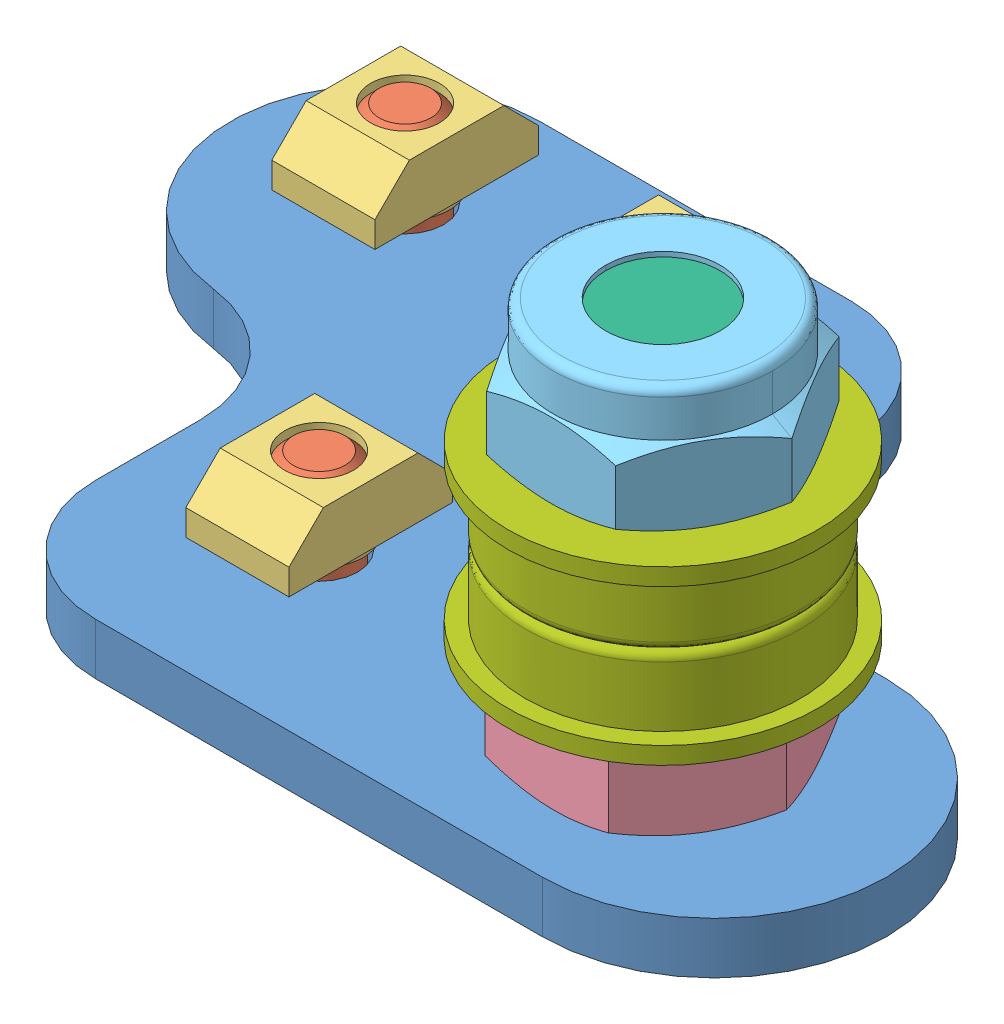
SolidWorks assembly pulley mount, configuration 默认. Lengths in mm.
Overall size (57.16 30.08 38).
12 component instances, 7 part files, 23 mates.
Components (placement in the parent):
- Y Adjustment Block-1: Y Adjustment Block [Y轴被动块] at (-6.4011 1.0269 53.16) size (57.16 3 38)
- M4X8 Socket Head Screw-1: M4X8 Socket Head Screw [默认] at (-25.4011 -3.4732 46.16) x (0 1 0) z (0 0 1) size (12 6.8 6.8)
- M4X8 Socket Head Screw-2: M4X8 Socket Head Screw [默认] at (-10.4011 -3.4732 46.16) x (0 1 0) z (0 0 1) size (12 6.8 6.8)
- M4X8 Socket Head Screw-3: M4X8 Socket Head Screw [默认] at (-10.4011 -3.4732 66.16) x (0 1 0) z (0 0 1) size (12 6.8 6.8)
- M4 T-Slot Nut-1: M4 T-Slot Nut [默认] at (-10.4011 1.8641 46.16) x (1 0 0) z (0 1 0) size (6 9.5 4.1)
- M4 T-Slot Nut-2: M4 T-Slot Nut [默认] at (-25.4011 1.8641 46.16) x (1 0 0) z (0 1 0) size (6 9.5 4.1)
- M4 T-Slot Nut-3: M4 T-Slot Nut [默认] at (-10.4011 1.8641 66.16) x (1 0 0) z (0 1 0) size (6 9.5 4.1)
- M8 nut-1: M8 nut [默认] at (9.5989 5.0268 66.16) x (0.999121 0 0.041925) z (0 1 0) size (15.01 13 5.5)
- M8 Self-locking nut-1: M8 Self-locking nut [默认] at (9.5989 19.8593 66.16) x (1 0 0) z (0 1 0) size (15.01 13 7.18)
- M8X25 Pan Head Screw-1: M8X25 Pan Head Screw [默认] at (9.5989 -7.8732 66.16) x (0 1 0) z (0 0 1) size (29.8 14 14)
- F688 pillow-1: F688 pillow [默认] at (9.5989 5.0268 66.16) size (18 5 18)
- F688 pillow-2: F688 pillow [默认] at (9.5989 15.0268 66.16) x (1 0 0) z (0 0 -1) size (18 5 18)
Mates (geometry in assembly coordinates):
- 同心1: concentric aligned: cylinder of Y Adjustment Block-1 through (-25.4011 -5.4732 46.16) axis (0 -1 0) radius 2.25; cylinder of M4X8 Socket Head Screw-1 through (-25.4011 -4.4148 46.16) axis (0 -1 0) radius 2
- 同心2: concentric aligned: cylinder of Y Adjustment Block-1 through (-10.4011 -5.4732 46.16) axis (0 -1 0) radius 2.25; cylinder of M4X8 Socket Head Screw-2 through (-10.4011 -4.4148 46.16) axis (0 -1 0) radius 2
- 同心3: concentric aligned: cylinder of Y Adjustment Block-1 through (-10.4011 -0.4732 66.16) axis (0 -1 0) radius 2.25; cylinder of M4X8 Socket Head Screw-3 through (-10.4011 -4.4148 66.16) axis (0 -1 0) radius 2
- 重合1: coincident anti-aligned: plane of Y Adjustment Block-1 through (0.0989 -3.4732 66.16) normal (0 -1 0); plane of M4X8 Socket Head Screw-2 through (-13.8011 -3.4732 46.16) normal (0 1 0)
- 重合2: coincident anti-aligned: plane of Y Adjustment Block-1 through (0.0989 -3.4732 66.16) normal (0 -1 0); plane of M4X8 Socket Head Screw-1 through (-28.8011 -3.4732 46.16) normal (0 1 0)
- 重合3: coincident anti-aligned: plane of Y Adjustment Block-1 through (0.0989 -3.4732 66.16) normal (0 -1 0); plane of M4X8 Socket Head Screw-3 through (-13.8011 -3.4732 66.16) normal (0 1 0)
- 同心4: concentric aligned: cylinder of M4X8 Socket Head Screw-3 through (-10.4011 -4.4148 66.16) axis (0 -1 0) radius 2; cylinder of M4 T-Slot Nut-3 through (-10.4011 4.7931 66.16) axis (0 -1 0) radius 2
- 同心5: concentric aligned: cylinder of M4X8 Socket Head Screw-1 through (-25.4011 -4.4148 46.16) axis (0 -1 0) radius 2; cylinder of M4 T-Slot Nut-2 through (-25.4011 4.7931 46.16) axis (0 -1 0) radius 2
- 同心6: concentric aligned: cylinder of M4X8 Socket Head Screw-2 through (-10.4011 -4.4148 46.16) axis (0 -1 0) radius 2; cylinder of M4 T-Slot Nut-1 through (-10.4011 4.7931 46.16) axis (0 -1 0) radius 2
- 垂直1: perpendicular: plane of Y Adjustment Block-1 through (22.5989 -0.4732 76.16) normal (0 0 1); plane of M4 T-Slot Nut-3 through (-7.4011 1.8641 66.16) normal (1 0 0)
- 平行2: parallel aligned: plane of M4 T-Slot Nut-1 through (-7.4011 1.8641 46.16) normal (1 0 0); plane of M4 T-Slot Nut-3 through (-7.4011 1.8641 66.16) normal (1 0 0)
- 平行3: parallel aligned: plane of M4 T-Slot Nut-2 through (-22.4011 1.8641 46.16) normal (1 0 0); plane of M4 T-Slot Nut-3 through (-7.4011 1.8641 66.16) normal (1 0 0)
- 重合7: coincident aligned: plane of M4X8 Socket Head Screw-3 through (-10.4011 4.5268 66.16) normal (0 1 0); plane of M4 T-Slot Nut-3 through (-7.4011 4.5268 63.41) normal (0 1 0)
- 重合8: coincident aligned: plane of M4X8 Socket Head Screw-1 through (-25.4011 4.5268 46.16) normal (0 1 0); plane of M4 T-Slot Nut-2 through (-22.4011 4.5268 43.41) normal (0 1 0)
- 重合9: coincident aligned: plane of M4X8 Socket Head Screw-2 through (-10.4011 4.5268 46.16) normal (0 1 0); plane of M4 T-Slot Nut-1 through (-7.4011 4.5268 43.41) normal (0 1 0)
- 重合10: coincident anti-aligned: plane of Y Adjustment Block-1 through (0.0989 -3.4732 66.16) normal (0 -1 0); plane of M8X25 Pan Head Screw-1 through (9.5989 -3.4732 66.16) normal (0 1 0)
- 同心7: concentric aligned: cylinder of Y Adjustment Block-1 through (9.5989 -5.4732 66.16) axis (0 -1 0) radius 4.05; cylinder of M8X25 Pan Head Screw-1 through (9.5989 6.5268 66.16) axis (0 -1 0) radius 4
- 同心8: concentric anti-aligned: cylinder of M8 nut-1 through (9.5989 7.3339 66.16) axis (0 1 0) radius 3.3235; cylinder of M8X25 Pan Head Screw-1 through (9.5989 6.5268 66.16) axis (0 -1 0) radius 4
- 重合12: coincident anti-aligned: plane of M8 nut-1 through (9.0539 14.1339 79.1486) normal (0 1 0); plane of F688 pillow-1 through (9.5989 14.1339 66.16) normal (0 -1 0)
- 同心9: concentric aligned: cylinder of M8X25 Pan Head Screw-1 through (9.5989 6.5268 66.16) axis (0 -1 0) radius 4; cylinder of F688 pillow-1 through (9.5989 19.1339 66.16) axis (0 -1 0) radius 4
- 重合13: coincident anti-aligned: plane of M8 Self-locking nut-1 through (-1.6594 24.1339 72.66) normal (0 -1 0); plane of F688 pillow-2 through (9.5989 24.1339 66.16) normal (0 1 0)
- 同心10: concentric anti-aligned: cylinder of M8 Self-locking nut-1 through (9.5989 23.8163 66.16) axis (0 1 0) radius 3.3235; cylinder of M8X25 Pan Head Screw-1 through (9.5989 6.5268 66.16) axis (0 -1 0) radius 4
- 重合14: coincident anti-aligned: plane of Y Adjustment Block-1 through (0.0989 -0.4732 66.16) normal (0 1 0); plane of M8 nut-1 through (-2.5188 -0.4732 64.0251) normal (0 -1 0)
